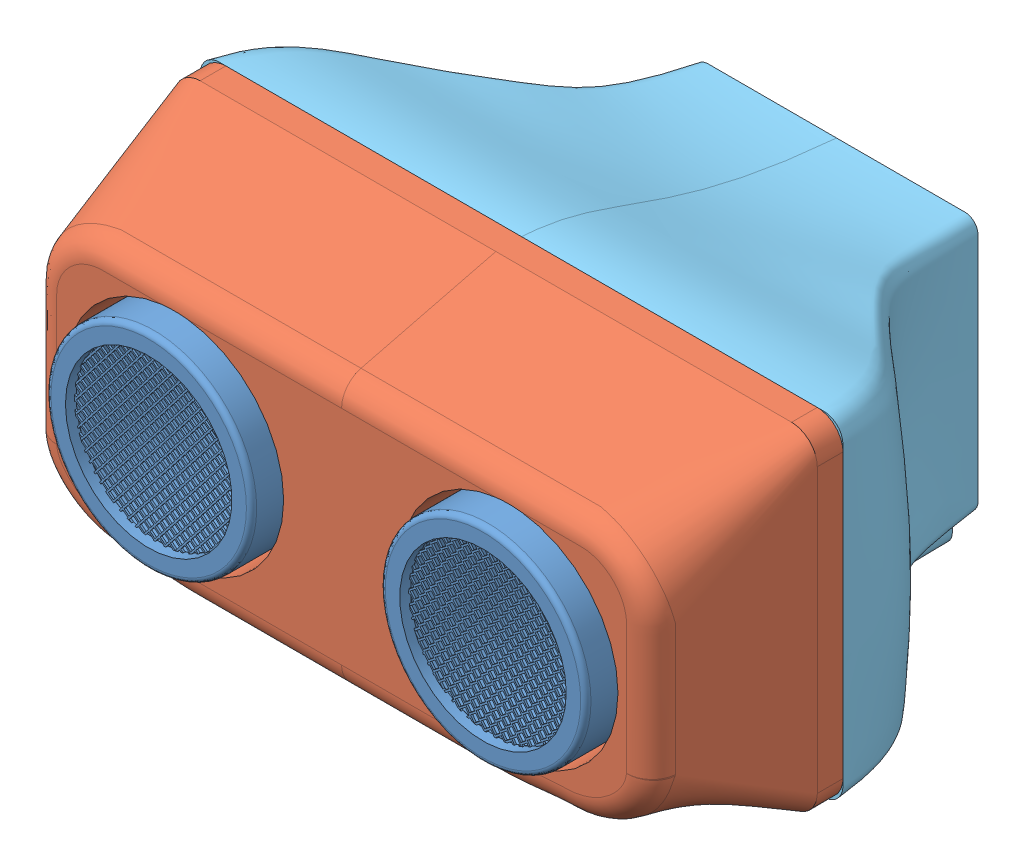
SolidWorks assembly Piezo, configuration Default. Lengths in mm.
Overall size (50.1 38.25 40.6).
5 component instances, 5 part files, 11 mates.
Components (placement in the parent):
- Sensor Ultrasónico-1: Sensor Ultrasónico [Predeterminado] at (17.3287 26.6319 31.4962) size (45.42 26.14 17.7)
- Cap-1: Cap [Default] at (17.3287 24.6319 29.4962) size (50.1 30.07 14.41)
- board-1: board [Default] at (17.3287 14.8619 18.6462) x (0 0 1) z (0 1 0) size (22.5 16 1.6)
- RJ12draft-1: RJ12draft [Default] at (17.3287 23.9619 2.8962) size (12 15 13)
- Back-1: Back [Default] at (17.3287 24.477 27.4962) x (-1 0 0) z (0 0 -1) size (50.02 38.21 24.52)
Mates (geometry in assembly coordinates):
- Concentric1: concentric anti-aligned: cylinder of Sensor Ultrasónico-1 through (4.3287 26.6319 43.4962) axis (0 0 -1) radius 8; cylinder of Cap-1 through (4.3287 26.6319 27.4961) axis (0 0 1) radius 8.5
- Concentric2: concentric anti-aligned: cylinder of Sensor Ultrasónico-1 through (30.3287 26.6319 43.4962) axis (0 0 -1) radius 8; cylinder of Cap-1 through (30.3287 26.6319 27.4961) axis (0 0 1) radius 8.5
- Coincident1: coincident anti-aligned: plane of Sensor Ultrasónico-1 through (-5.3813 16.4619 29.8962) normal (0 -1 0); plane of board-1 through (17.3287 16.4619 18.6462) normal (0 1 0)
- Coincident2: coincident anti-aligned: plane of Sensor Ultrasónico-1 through (17.3287 26.6319 29.8962) normal (0 0 -1); plane of board-1 through (25.3287 16.4619 29.8962) normal (0 0 1)
- Coincident3: coincident aligned: plane of Sensor Ultrasónico-1 through (17.3287 26.6319 31.4962) normal (1 0 0); plane of board-1
- Coincident4: coincident aligned: plane of board-1; plane of RJ12draft-1 through (17.3287 23.9619 2.8962) normal (1 0 0)
- Coincident5: coincident anti-aligned: plane of board-1 through (17.3287 16.4619 18.6462) normal (0 1 0); plane of RJ12draft-1 through (11.3287 16.4619 15.8962) normal (0 -1 0)
- Distance1: distance = 14 mm anti-aligned: plane of RJ12draft-1 through (17.3287 23.9619 15.8962) normal (0 0 1); plane of Sensor Ultrasónico-1 through (17.3287 26.6319 29.8962) normal (0 0 -1)
- Coincident8: coincident anti-aligned: plane of Sensor Ultrasónico-1 through (17.3287 26.6319 31.4962) normal (0 0 1); plane of Cap-1 through (17.3287 24.6319 31.4962) normal (0 0 -1)
- Coincident9: coincident aligned: line of Cap-1 through (40.3287 39.6319 27.4962) axis (-1 0 0); line of Back-1 through (40.8287 39.6319 27.4962) axis (-1 0 0)
- Coincident10: coincident aligned: line of Cap-1 through (-7.6713 15.6319 27.4962) axis (0 1 0); line of Back-1 through (-7.6713 15.1319 27.4962) axis (0 1 0)
